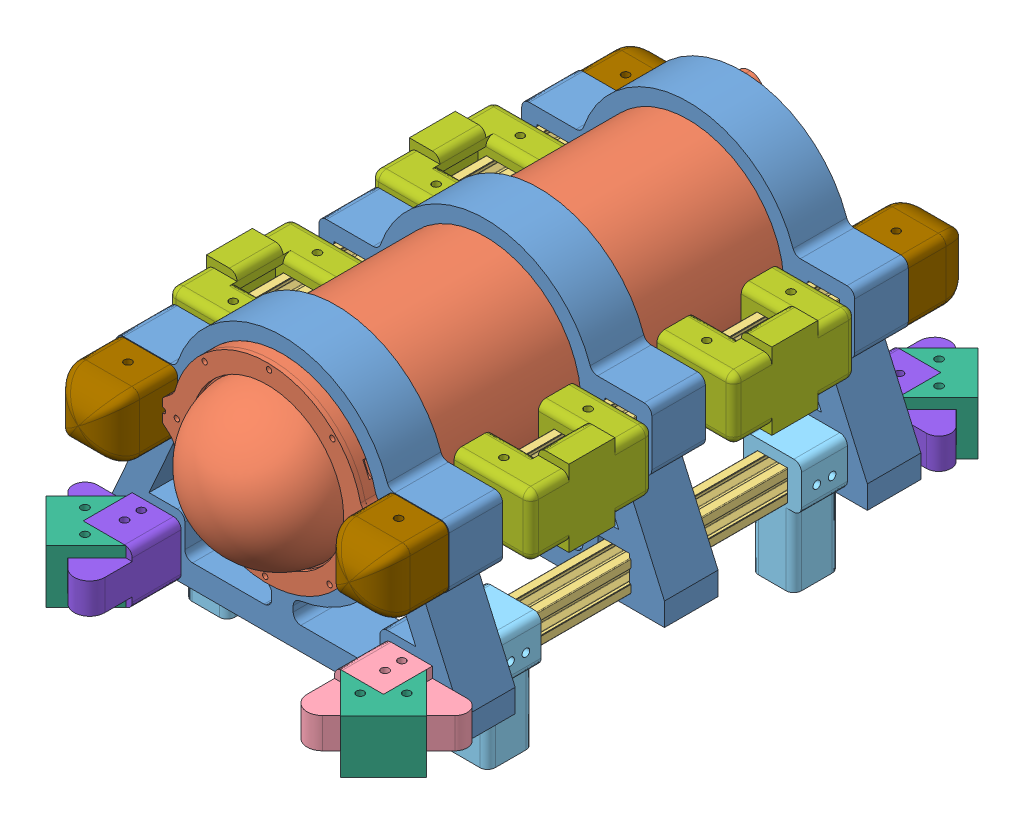
SolidWorks assembly aracsonson, configuration Varsayılan. Lengths in mm.
Overall size (257.51 215.21 419.72).
29 component instances, 9 part files, 64 mates.
Components (placement in the parent):
- tup30cmbirlesik-1: tup30cmbirlesik [Varsayılan] at (-12.712 13.1831 -30.3728) size (234 173.21 358.25)
  - auv_on-1: auv_on [Varsayılan] at (-0.4985 6.4776 216.5) size (234 172.66 35)
  - auvtup30cm-1: auvtup30cm [Default] at (13.0956 8.6338 230.5) x (0.999767 -0.021578 0) z (0 0 1) size (143.05 134.03 358.25)
  - auv_on-2: auv_on [Varsayılan] at (-0.4985 6.4776 349) size (234 172.66 35)
  - auv_on-3: auv_on [Varsayılan] at (-0.4985 6.4776 481.5) size (234 172.66 35)
- sigma_20x20x1000-1: sigma_20x20x1000 [Varsayılan] at (71.7895 -62.5006 161.1272) x (0 0 1) z (-1 0 0) size (350 20 20)
- sigma_20x20x1000-2: sigma_20x20x1000 [Varsayılan] at (75.1683 19.479 161.1272) x (0 0 1) z (-1 0 0) size (350 20 20)
- sigma_20x20x1000-3: sigma_20x20x1000 [Varsayılan] at (-98.3505 -62.5006 161.1272) x (0 0 1) z (-1 0 0) size (350 20 20)
- sigma_20x20x1000-4: sigma_20x20x1000 [Varsayılan] at (-101.5893 19.479 161.1272) x (0 0 1) z (-1 0 0) size (350 20 20)
- motortutucuon_ters-1: motortutucuon_ters [Varsayılan] at (77.9913 -52.5006 504.2544) x (-1 0 0) z (0 -1 0) size (62.69 59.86 35)
- motortutucuon_ters-2: motortutucuon_ters [Varsayılan] at (-104.5523 -52.5006 168) x (1 0 0) z (0 -1 0) size (62.69 59.86 35)
- ayak-1: ayak [Varsayılan] at (-108.3505 -72.5006 421.1272) size (38 77 30)
- ayak-2: ayak [Varsayılan] at (-108.3505 -72.5006 221.1272) size (38 77 30)
- ayak-3: ayak [Varsayılan] at (61.7895 -72.5006 221.1272) size (38 77 30)
- ayak-4: ayak [Varsayılan] at (61.7895 -72.5006 421.1272) size (38 77 30)
- motortutucuarka-1: motortutucuarka [Varsayılan] at (107.3992 -77.5006 512.737) x (-0.707107 0 0.707107) z (-0.707107 0 -0.707107) size (39.6 35 36.98)
- motortutucuarka-2: motortutucuarka [Varsayılan] at (-105.9602 -77.5006 540.73) x (-0.707107 0 -0.707107) z (0.707107 0 -0.707107) size (39.6 35 36.98)
- motortutucuarka-3: motortutucuarka [Varsayılan] at (-133.9602 -77.5006 159.5175) x (0.707107 0 -0.707107) z (0.707107 0 0.707107) size (39.6 35 36.98)
- motortutucuarka-4: motortutucuarka [Varsayılan] at (79.3992 -77.5006 131.5245) x (0.707107 0 0.707107) z (-0.707107 0 0.707107) size (39.6 35 36.98)
- motorusttutucu-1: motorusttutucu [Varsayılan] at (55.1683 -0.521 362.3772) size (50 50 80)
- motorusttutucu-2: motorusttutucu [Varsayılan] at (55.1683 -0.521 229.8772) size (50 50 80)
- motorusttutucu-3: motorusttutucu [Varsayılan] at (-81.5893 39.479 229.8772) x (-1 0 0) z (0 0 1) size (50 50 80)
- motorusttutucu-4: motorusttutucu [Varsayılan] at (-81.5893 39.479 362.3772) x (-1 0 0) z (0 0 1) size (50 50 80)
- motortutucuon-1: motortutucuon [Varsayılan] at (-104.5523 -72.5006 504.2544) x (1 0 0) z (0 1 0) size (62.69 59.86 35)
- motortutucuon-2: motortutucuon [Varsayılan] at (77.9913 -72.5006 168) x (-1 0 0) z (0 1 0) size (62.69 59.86 35)
- kapak-1: kapak [Varsayılan] at (-111.5893 9.479 486.1272) size (40 40 45)
- kapak-2: kapak [Varsayılan] at (65.1683 9.479 486.1272) size (40 40 45)
- kapak-3: kapak [Varsayılan] at (-91.5893 9.479 186.1272) x (-1 0 0) z (0 0 -1) size (40 40 45)
- kapak-4: kapak [Varsayılan] at (85.1683 9.479 186.1272) x (-1 0 0) z (0 0 -1) size (40 40 45)
Mates (geometry in assembly coordinates):
- Coincident1: coincident: plane of tup30cmbirlesik-1/auv_on-2 through (-13.2105 -52.5006 353.6272) normal (0 -1 0); plane of sigma_20x20x1000-1 through (62.2895 -52.5006 511.1272) normal (0 1 0)
- Coincident2: coincident: plane of tup30cmbirlesik-1/auv_on-3 through (61.7895 19.6607 486.1272) normal (1 0 0); plane of sigma_20x20x1000-1 through (61.7895 -57.8506 511.1272) normal (-1 0 0)
- Coincident3: coincident: plane of tup30cmbirlesik-1/auv_on-3 through (-13.2105 29.479 486.1272) normal (0 -1 0); plane of sigma_20x20x1000-2 through (65.6683 29.479 511.1272) normal (0 1 0)
- Coincident4: coincident: plane of tup30cmbirlesik-1/auv_on-3 through (65.1683 19.6607 486.1272) normal (1 0 0); line of sigma_20x20x1000-2 through (65.1683 14.829 511.1272) axis (0 0 -1)
- Coincident5: coincident: plane of tup30cmbirlesik-1/auv_on-3 through (-111.5893 19.6607 486.1272) normal (1 0 0); plane of sigma_20x20x1000-4 through (-111.5893 24.129 511.1272) normal (-1 0 0)
- Coincident6: coincident: plane of tup30cmbirlesik-1/auv_on-3 through (-13.2105 29.479 486.1272) normal (0 -1 0); plane of sigma_20x20x1000-4 through (-111.0893 29.479 511.1272) normal (0 1 0)
- Coincident7: coincident: plane of tup30cmbirlesik-1/auv_on-3 through (-13.2105 -72.5006 486.1272) normal (0 1 0); plane of sigma_20x20x1000-3 through (-103.0005 -72.5006 511.1272) normal (0 -1 0)
- Coincident8: coincident: plane of tup30cmbirlesik-1/auv_on-3 through (-108.3505 19.6607 486.1272) normal (1 0 0); plane of sigma_20x20x1000-3 through (-108.3505 -72.0006 511.1272) normal (-1 0 0)
- Coincident11: coincident anti-aligned: plane of sigma_20x20x1000-1 through (81.7895 -67.1506 511.1272) normal (1 0 0); plane of motortutucuon - Copy (2)-1 through (81.7895 -72.5006 504.2544) normal (-1 0 0)
- Coincident12: coincident anti-aligned: plane of sigma_20x20x1000-1 through (81.2895 -72.5006 511.1272) normal (0 -1 0); plane of motortutucuon - Copy (2)-1 through (77.9913 -72.5006 504.2544) normal (0 1 0)
- Width1: width: plane of sigma_20x20x1000-1 through (64.9324 -57.3506 511.1272) normal (0 0 1); plane of sigma_20x20x1000-1 through (64.9324 -57.3506 161.1272) normal (0 0 -1); plane of tup30cmbirlesik-1/auv_on-1 through (-13.2105 19.6607 186.1272) normal (0 0 -1); plane of tup30cmbirlesik-1/auv_on-3 through (-13.2105 19.6607 486.1272) normal (0 0 1)
- Width2: width: plane of sigma_20x20x1000-2 through (68.3112 24.629 161.1272) normal (0 0 -1); plane of sigma_20x20x1000-2 through (68.3112 24.629 511.1272) normal (0 0 1); plane of tup30cmbirlesik-1/auv_on-3 through (-13.2105 19.6607 486.1272) normal (0 0 1); plane of tup30cmbirlesik-1/auv_on-1 through (-13.2105 19.6607 186.1272) normal (0 0 -1)
- Width3: width: plane of sigma_20x20x1000-4 through (-108.4464 24.629 511.1272) normal (0 0 1); plane of sigma_20x20x1000-4 through (-108.4464 24.629 161.1272) normal (0 0 -1); plane of tup30cmbirlesik-1/auv_on-1 through (-13.2105 19.6607 186.1272) normal (0 0 -1); plane of tup30cmbirlesik-1/auv_on-3 through (-13.2105 19.6607 486.1272) normal (0 0 1)
- Width4: width: plane of sigma_20x20x1000-3 through (-105.2076 -57.3506 511.1272) normal (0 0 1); plane of sigma_20x20x1000-3 through (-105.2076 -57.3506 161.1272) normal (0 0 -1); plane of tup30cmbirlesik-1/auv_on-1 through (-13.2105 19.6607 186.1272) normal (0 0 -1); plane of tup30cmbirlesik-1/auv_on-3 through (-13.2105 19.6607 486.1272) normal (0 0 1)
- Coincident13: coincident anti-aligned: line of sigma_20x20x1000-1 through (61.7895 -53.0006 511.1272) axis (0 -1 0); line of motortutucuon - Copy (2)-1 through (61.7895 -72.5006 511.1272) axis (0 1 0)
- Coincident17: coincident aligned: line of sigma_20x20x1000-3 through (-88.3505 -57.8506 161.1272) axis (0 1 0); line of motortutucuon - Copy (2)-2 through (-88.3505 -72.5006 161.1272) axis (0 1 0)
- Coincident18: coincident aligned: line of sigma_20x20x1000-3 through (-107.8505 -72.5006 161.1272) axis (1 0 0); line of motortutucuon - Copy (2)-2 through (-108.3505 -72.5006 161.1272) axis (1 0 0)
- Coincident23: coincident anti-aligned: plane of sigma_20x20x1000-3 through (-103.0005 -72.5006 511.1272) normal (0 -1 0); plane of ayak-2 through (-108.3505 -72.5006 251.1272) normal (0 1 0)
- Coincident24: coincident: point of assembly; point of assembly; moEndPointRef_w of tup30cmbirlesik-1/auv_on-1; moEndPointRef_w of ayak-2
- Coincident25: coincident anti-aligned: plane of sigma_20x20x1000-3 through (-108.3505 -72.0006 511.1272) normal (-1 0 0); plane of ayak-1 through (-108.3505 -72.5006 451.1272) normal (1 0 0)
- Coincident26: coincident: point of assembly; point of assembly; moEndPointRef_w of tup30cmbirlesik-1/auv_on-3; moEndPointRef_w of ayak-1
- Coincident27: coincident anti-aligned: plane of sigma_20x20x1000-3 through (-103.0005 -72.5006 511.1272) normal (0 -1 0); plane of ayak-1 through (-108.3505 -72.5006 451.1272) normal (0 1 0)
- Coincident28: coincident anti-aligned: plane of sigma_20x20x1000-3 through (-108.3505 -72.0006 511.1272) normal (-1 0 0); plane of ayak-2 through (-108.3505 -72.5006 251.1272) normal (1 0 0)
- Coincident29: coincident anti-aligned: plane of sigma_20x20x1000-1 through (81.7895 -67.1506 511.1272) normal (1 0 0); plane of ayak-4 through (81.7895 -72.5006 451.1272) normal (-1 0 0)
- Coincident30: coincident: point of assembly; point of assembly; moEndPointRef_w of tup30cmbirlesik-1/auv_on-3; moEndPointRef_w of ayak-4
- Coincident31: coincident anti-aligned: plane of sigma_20x20x1000-1 through (62.2895 -52.5006 511.1272) normal (0 1 0); plane of ayak-4 through (61.7895 -52.5006 451.1272) normal (0 -1 0)
- Coincident32: coincident anti-aligned: plane of sigma_20x20x1000-1 through (81.7895 -67.1506 511.1272) normal (1 0 0); plane of ayak-3 through (81.7895 -72.5006 251.1272) normal (-1 0 0)
- Coincident33: coincident: point of assembly; point of assembly; moEndPointRef_w of tup30cmbirlesik-1/auv_on-1; moEndPointRef_w of ayak-3
- Coincident34: coincident anti-aligned: plane of sigma_20x20x1000-1 through (76.4395 -52.5006 511.1272) normal (0 1 0); plane of ayak-3 through (61.7895 -52.5006 251.1272) normal (0 -1 0)
- Coincident36: coincident anti-aligned: line of motortutucuon - Copy (2)-1 through (57.7895 -45.5006 518.1272) axis (1 0 0); line of motortutucuarka-1 through (84.7895 -45.5006 518.1272) axis (-1 0 0)
- Coincident37: coincident anti-aligned: line of motortutucuon - Copy (2)-1 through (84.7895 -45.5006 518.1272) axis (0 0 -1); line of motortutucuarka-1 through (84.7895 -45.5006 490.1272) axis (0 0 1)
- Coincident45: coincident anti-aligned: line of motortutucuon - Copy (2)-2 through (-84.3505 -45.5006 154.1272) axis (-1 0 0); line of motortutucuarka-3 through (-111.3505 -45.5006 154.1272) axis (1 0 0)
- Coincident46: coincident anti-aligned: line of motortutucuon - Copy (2)-2 through (-111.3505 -45.5006 154.1272) axis (0 0 1); line of motortutucuarka-3 through (-111.3505 -45.5006 182.1272) axis (0 0 -1)
- Coincident47: coincident anti-aligned: plane of sigma_20x20x1000-2 through (79.8183 29.479 511.1272) normal (0 1 0); plane of motorusttutucu-1 through (65.1683 29.479 387.3772) normal (0 -1 0)
- Coincident48: coincident anti-aligned: plane of sigma_20x20x1000-2 through (65.1683 24.129 511.1272) normal (-1 0 0); plane of motorusttutucu-1 through (65.1683 9.479 387.3772) normal (1 0 0)
- Width5: width: plane of tup30cmbirlesik-1/auv_on-3 through (-13.2105 19.6607 451.1272) normal (0 0 -1); plane of tup30cmbirlesik-1/auv_on-2 through (-13.2105 19.6607 353.6272) normal (0 0 1); plane of motorusttutucu-1 through (55.1683 -0.521 362.3772) normal (0 0 -1); plane of motorusttutucu-1 through (55.1683 -0.521 442.3772) normal (0 0 1)
- Coincident49: coincident anti-aligned: plane of sigma_20x20x1000-2 through (85.1683 28.979 511.1272) normal (1 0 0); plane of motorusttutucu-2 through (85.1683 9.479 254.8772) normal (-1 0 0)
- Coincident50: coincident anti-aligned: plane of sigma_20x20x1000-2 through (65.6683 29.479 511.1272) normal (0 1 0); plane of motorusttutucu-2 through (65.1683 29.479 254.8772) normal (0 -1 0)
- Width6: width: plane of tup30cmbirlesik-1/auv_on-2 through (-13.2105 19.6607 318.6272) normal (0 0 -1); plane of tup30cmbirlesik-1/auv_on-1 through (-13.2105 19.6607 221.1272) normal (0 0 1); plane of motorusttutucu-2 through (55.1683 -0.521 309.8772) normal (0 0 1); plane of motorusttutucu-2 through (55.1683 -0.521 229.8772) normal (0 0 -1)
- Coincident51: coincident anti-aligned: plane of sigma_20x20x1000-4 through (-111.0893 29.479 511.1272) normal (0 1 0); plane of motorusttutucu-4 through (-91.5893 29.479 387.3772) normal (0 -1 0)
- Coincident52: coincident anti-aligned: plane of sigma_20x20x1000-4 through (-91.5893 28.979 511.1272) normal (1 0 0); plane of motorusttutucu-4 through (-91.5893 29.479 387.3772) normal (-1 0 0)
- Width9: width: plane of motorusttutucu-4 through (-81.5893 39.479 442.3772) normal (0 0 1); plane of motorusttutucu-4 through (-81.5893 39.479 362.3772) normal (0 0 -1); plane of tup30cmbirlesik-1/auv_on-2 through (-13.2105 19.6607 318.6272) normal (0 0 -1); plane of tup30cmbirlesik-1/auv_on-3 through (-13.2105 19.6607 486.1272) normal (0 0 1)
- Coincident55: coincident anti-aligned: plane of sigma_20x20x1000-4 through (-106.2393 9.479 511.1272) normal (0 -1 0); plane of motorusttutucu-3 through (-91.5893 9.479 309.8772) normal (0 1 0)
- Coincident56: coincident anti-aligned: plane of sigma_20x20x1000-4 through (-91.5893 28.979 511.1272) normal (1 0 0); plane of motorusttutucu-3 through (-91.5893 29.479 309.8772) normal (-1 0 0)
- Width10: width: plane of motorusttutucu-3 through (-81.5893 39.479 309.8772) normal (0 0 1); plane of motorusttutucu-3 through (-81.5893 39.479 229.8772) normal (0 0 -1); plane of tup30cmbirlesik-1/auv_on-2 through (-13.2105 19.6607 318.6272) normal (0 0 -1); plane of tup30cmbirlesik-1/auv_on-1 through (-13.2105 19.6607 221.1272) normal (0 0 1)
- Coincident67: coincident anti-aligned: plane of sigma_20x20x1000-3 through (-103.0005 -72.5006 511.1272) normal (0 -1 0); plane of motortutucuon-1 through (-104.5523 -72.5006 504.2544) normal (0 1 0)
- Coincident68: coincident anti-aligned: plane of sigma_20x20x1000-3 through (-88.3505 -67.1506 511.1272) normal (1 0 0); plane of motortutucuon-1 through (-88.3505 -52.5006 504.2544) normal (-1 0 0)
- Coincident69: coincident: point of assembly; point of assembly; moEndPointRef_w of tup30cmbirlesik-1/auv_on-3; moEndPointRef_w of motortutucuon-1
- Coincident70: coincident aligned: circle of motortutucuarka-2; circle of motortutucuon-1
- Parallel1: parallel anti-aligned: line of motortutucuarka-2 through (-83.3505 -45.5006 518.1202) axis (-1 0 0); line of motortutucuon-1 through (-111.3505 -45.5006 518.1272) axis (1 0 0)
- Coincident73: coincident anti-aligned: plane of sigma_20x20x1000-1 through (61.7895 -57.8506 511.1272) normal (-1 0 0); plane of motortutucuon-2 through (61.7895 -52.5006 168) normal (1 0 0)
- Coincident74: coincident anti-aligned: plane of sigma_20x20x1000-1 through (81.2895 -72.5006 511.1272) normal (0 -1 0); plane of motortutucuon-2 through (77.9913 -72.5006 168) normal (0 1 0)
- Coincident75: coincident: line of assembly; point of assembly; line of tup30cmbirlesik-1/auv_on-1 through (81.7895 -52.5006 186.1272) axis (-1 0 0); moEndPointRef_w of motortutucuon-2
- Coincident76: coincident aligned: circle of motortutucuarka-4; circle of motortutucuon-2
- Parallel2: parallel anti-aligned: line of motortutucuarka-4 through (56.7895 -45.5006 154.1342) axis (1 0 0); line of motortutucuon-2 through (84.7895 -45.5006 154.1272) axis (-1 0 0)
- Coincident78: coincident: line of tup30cmbirlesik-1/auv_on-3 through (-116.5893 39.479 486.1272) axis (1 0 0); line of kapak-1 through (-86.5893 39.479 486.1272) axis (-1 0 0)
- Coincident79: coincident: line of tup30cmbirlesik-1/auv_on-3 through (-121.5893 4.479 486.1272) axis (0 1 0); line of kapak-1 through (-121.5893 34.479 486.1272) axis (0 -1 0)
- Coincident80: coincident: line of tup30cmbirlesik-1/auv_on-3 through (90.1683 39.479 486.1272) axis (-1 0 0); line of kapak-2 through (90.1683 39.479 486.1272) axis (-1 0 0)
- Coincident81: coincident: line of tup30cmbirlesik-1/auv_on-3 through (95.1683 4.479 486.1272) axis (0 1 0); line of kapak-2 through (95.1683 4.479 486.1272) axis (0 1 0)
- Coincident82: coincident: line of tup30cmbirlesik-1/auv_on-1 through (-116.5893 39.479 186.1272) axis (1 0 0); line of kapak-3 through (-116.5893 39.479 186.1272) axis (1 0 0)
- Coincident83: coincident: plane of tup30cmbirlesik-1/auv_on-1 through (-121.5893 19.6607 221.1272) normal (-1 0 0); line of kapak-3 through (-121.5893 4.479 186.1272) axis (0 1 0)
- Coincident84: coincident: line of tup30cmbirlesik-1/auv_on-1 through (-121.5893 4.479 186.1272) axis (0 1 0); line of kapak-3 through (-121.5893 4.479 186.1272) axis (0 1 0)
- Coincident85: coincident: line of tup30cmbirlesik-1/auv_on-1 through (90.1683 39.479 186.1272) axis (-1 0 0); line of kapak-4 through (60.1683 39.479 186.1272) axis (1 0 0)
- Coincident86: coincident: line of tup30cmbirlesik-1/auv_on-1 through (95.1683 4.479 186.1272) axis (0 1 0); line of kapak-4 through (95.1683 34.479 186.1272) axis (0 -1 0)
